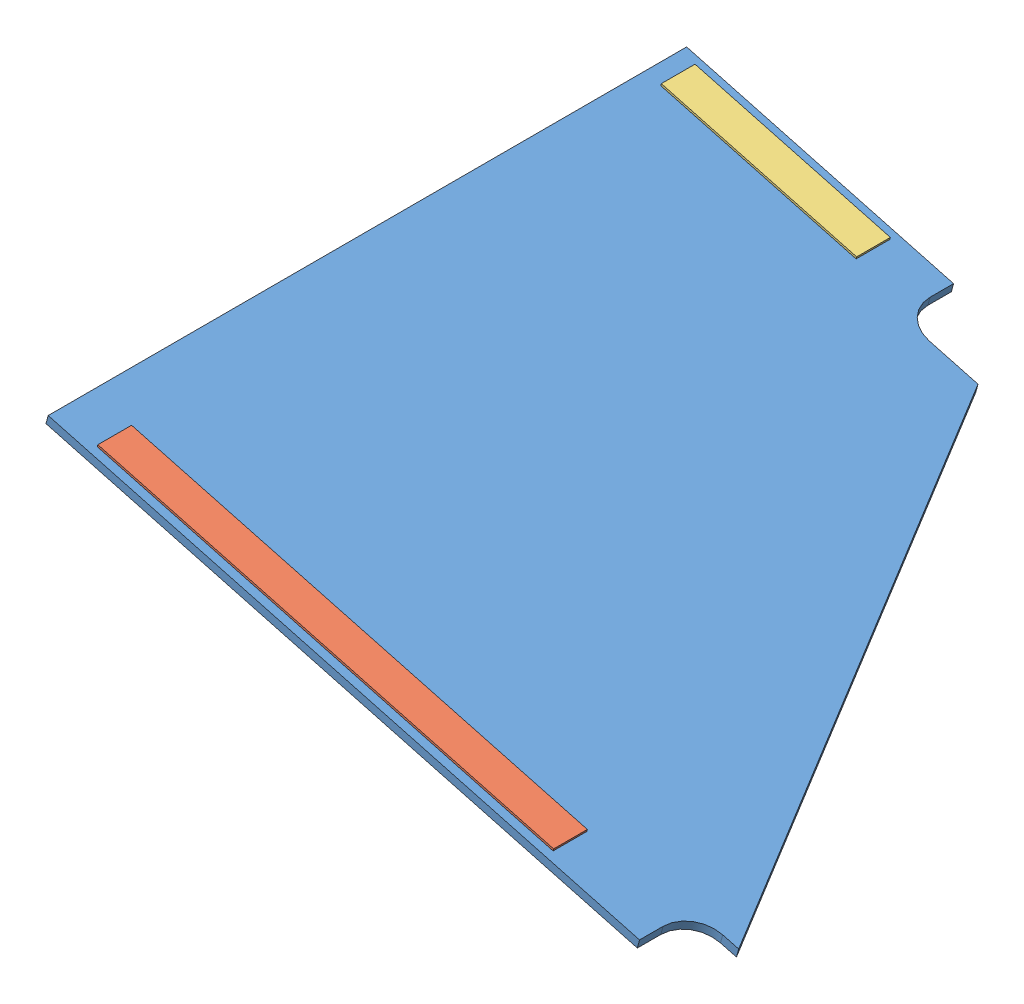
SolidWorks assembly GE-19181, configuration Default. Lengths in mm.
Overall size (481.38 134.68 481.12).
3 component instances, 3 part files, 6 mates.
Components (placement in the parent):
- GE-19115-1: GE-19115 [Default] at origin size (481.38 134.68 481.12)
- Loop_1_14-1: Loop_1_14 [Default] at (32.3116 -2.0839 -9.525) x (0.965926 -0.258819 0) z (0 0 1) size (355.6 1.59 25.4)
- Loop_1_6-1: Loop_1_6 [Default] at (13.9108 2.8466 -452.5434) x (0.965926 -0.258819 0) z (0 0 1) size (152.4 1.59 25.4)
Mates (geometry in assembly coordinates):
- Coincident1: coincident: plane of GE-19115-1 through (1.6435 6.1336 0) normal (0.258819 0.965926 0); plane of ? through (32.3116 -2.0839 -452.5434) normal (-0.258819 -0.965926 0)
- Distance1: distance = 6.35 mm: plane of GE-19115-1 through (-32.3131 -120.594 -484.2934) normal (0 0 -1); plane of Loop_1_6-1 through (14.3216 4.38 -477.9434) normal (0 0 -1)
- Coincident3: coincident: plane of GE-19115-1 through (1.6435 6.1336 0) normal (0.258819 0.965926 0); plane of Loop_1_14-1 through (32.3116 -2.0839 -9.525) normal (-0.258819 -0.965926 0)
- Distance2: distance = 12.7 mm: plane of GE-19115-1 through (1.6435 6.1336 -487.4684) normal (-0.965926 0.258819 0); plane of Loop_1_6-1 through (14.3216 4.38 -452.5434) normal (-0.965926 0.258819 0)
- Distance3: distance = 31.75 mm: plane of Loop_1_14-1 through (32.7225 -0.5505 -9.525) normal (-0.965926 0.258819 0); plane of GE-19115-1 through (1.6435 6.1336 -487.4684) normal (-0.965926 0.258819 0)
- Distance4: distance = 6.35 mm: plane of GE-19115-1 through (-32.3131 -120.594 -3.175) normal (0 0 1); plane of Loop_1_14-1 through (32.7225 -0.5505 -9.525) normal (0 0 1)
